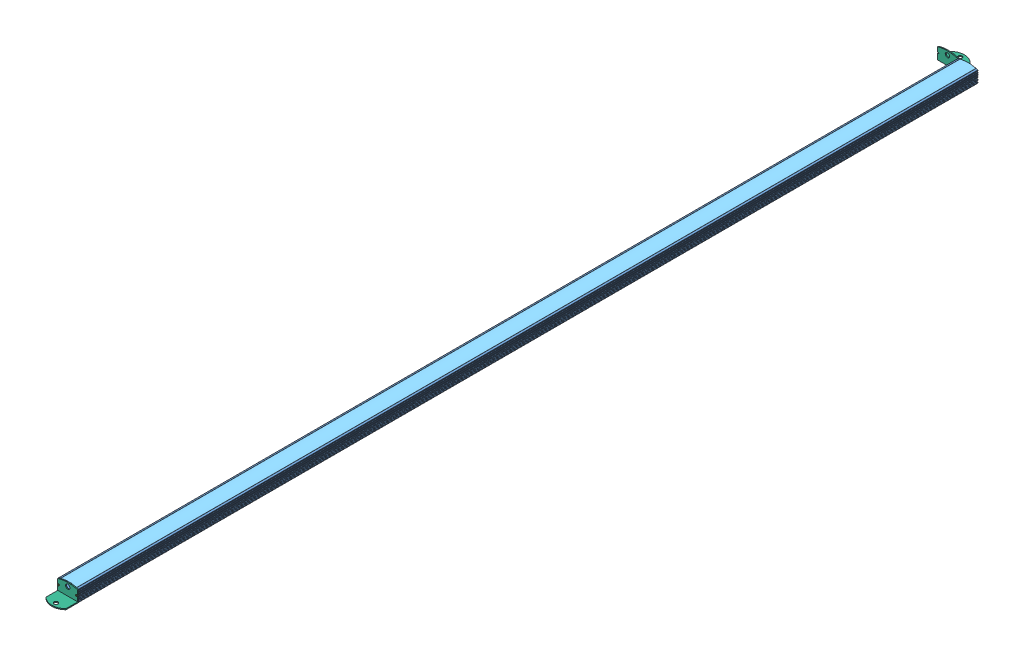
SolidWorks assembly lampara 54 leds, configuration Predeterminado. Lengths in mm.
Overall size (41.54 13.32 954.48).
132 component instances, 7 part files, 14 mates.
Components (placement in the parent):
- disipador-1: disipador [Predeterminado] at (27.3398 -156.7696 2146.1688) x (-1 0 0) z (0 -1 0) size (20.48 920 12.19)
- 5cmLedStrip-1: 5cmLedStrip [Default] at (81.127 -174.1929 2106.2883) x (0 0 1) z (-1 0 0) size (50.19 2.7 12.2)
  - stripPad-1: stripPad [Default] at (-20.1195 23.8233 53.0068) size (50.19 1.3 12.2)
  - led5050-1: led5050 [Default] at (-14.6195 25.2233 49.5068) size (5.4 1.5 5)
  - Resistor1206-1: Resistor1206 [Default] at (-2.8195 25.0233 48.6068) x (0 0 -1) z (1 0 0) size (3.2 0.7 1.6)
  - led5050-2: led5050 [Default] at (2.3805 25.2233 49.5068) size (5.4 1.5 5)
  - led5050-3: led5050 [Default] at (19.3805 25.2233 49.5068) size (5.4 1.5 5)
  - Resistor1206-2: Resistor1206 [Default] at (14.1805 25.0233 48.6068) x (0 0 -1) z (1 0 0) size (3.2 0.7 1.6)
- 5cmLedStrip-2: 5cmLedStrip [Default] at (81.127 -174.1929 2056.2883) x (0 0 1) z (-1 0 0) size (50.19 2.7 12.2)
  - stripPad-1: stripPad [Default] at (-20.1195 23.8233 53.0068) size (50.19 1.3 12.2)
  - led5050-1: led5050 [Default] at (-14.6195 25.2233 49.5068) size (5.4 1.5 5)
  - Resistor1206-1: Resistor1206 [Default] at (-2.8195 25.0233 48.6068) x (0 0 -1) z (1 0 0) size (3.2 0.7 1.6)
  - led5050-2: led5050 [Default] at (2.3805 25.2233 49.5068) size (5.4 1.5 5)
  - led5050-3: led5050 [Default] at (19.3805 25.2233 49.5068) size (5.4 1.5 5)
  - Resistor1206-2: Resistor1206 [Default] at (14.1805 25.0233 48.6068) x (0 0 -1) z (1 0 0) size (3.2 0.7 1.6)
- 5cmLedStrip-3: 5cmLedStrip [Default] at (81.127 -174.1929 2006.2883) x (0 0 1) z (-1 0 0) size (50.19 2.7 12.2)
  - stripPad-1: stripPad [Default] at (-20.1195 23.8233 53.0068) size (50.19 1.3 12.2)
  - led5050-1: led5050 [Default] at (-14.6195 25.2233 49.5068) size (5.4 1.5 5)
  - Resistor1206-1: Resistor1206 [Default] at (-2.8195 25.0233 48.6068) x (0 0 -1) z (1 0 0) size (3.2 0.7 1.6)
  - led5050-2: led5050 [Default] at (2.3805 25.2233 49.5068) size (5.4 1.5 5)
  - led5050-3: led5050 [Default] at (19.3805 25.2233 49.5068) size (5.4 1.5 5)
  - Resistor1206-2: Resistor1206 [Default] at (14.1805 25.0233 48.6068) x (0 0 -1) z (1 0 0) size (3.2 0.7 1.6)
- 5cmLedStrip-4: 5cmLedStrip [Default] at (81.127 -174.1929 1956.2883) x (0 0 1) z (-1 0 0) size (50.19 2.7 12.2)
  - stripPad-1: stripPad [Default] at (-20.1195 23.8233 53.0068) size (50.19 1.3 12.2)
  - led5050-1: led5050 [Default] at (-14.6195 25.2233 49.5068) size (5.4 1.5 5)
  - Resistor1206-1: Resistor1206 [Default] at (-2.8195 25.0233 48.6068) x (0 0 -1) z (1 0 0) size (3.2 0.7 1.6)
  - led5050-2: led5050 [Default] at (2.3805 25.2233 49.5068) size (5.4 1.5 5)
  - led5050-3: led5050 [Default] at (19.3805 25.2233 49.5068) size (5.4 1.5 5)
  - Resistor1206-2: Resistor1206 [Default] at (14.1805 25.0233 48.6068) x (0 0 -1) z (1 0 0) size (3.2 0.7 1.6)
- 5cmLedStrip-5: 5cmLedStrip [Default] at (81.127 -174.1929 1906.2883) x (0 0 1) z (-1 0 0) size (50.19 2.7 12.2)
  - stripPad-1: stripPad [Default] at (-20.1195 23.8233 53.0068) size (50.19 1.3 12.2)
  - led5050-1: led5050 [Default] at (-14.6195 25.2233 49.5068) size (5.4 1.5 5)
  - Resistor1206-1: Resistor1206 [Default] at (-2.8195 25.0233 48.6068) x (0 0 -1) z (1 0 0) size (3.2 0.7 1.6)
  - led5050-2: led5050 [Default] at (2.3805 25.2233 49.5068) size (5.4 1.5 5)
  - led5050-3: led5050 [Default] at (19.3805 25.2233 49.5068) size (5.4 1.5 5)
  - Resistor1206-2: Resistor1206 [Default] at (14.1805 25.0233 48.6068) x (0 0 -1) z (1 0 0) size (3.2 0.7 1.6)
- 5cmLedStrip-6: 5cmLedStrip [Default] at (81.127 -174.1929 1856.2883) x (0 0 1) z (-1 0 0) size (50.19 2.7 12.2)
  - stripPad-1: stripPad [Default] at (-20.1195 23.8233 53.0068) size (50.19 1.3 12.2)
  - led5050-1: led5050 [Default] at (-14.6195 25.2233 49.5068) size (5.4 1.5 5)
  - Resistor1206-1: Resistor1206 [Default] at (-2.8195 25.0233 48.6068) x (0 0 -1) z (1 0 0) size (3.2 0.7 1.6)
  - led5050-2: led5050 [Default] at (2.3805 25.2233 49.5068) size (5.4 1.5 5)
  - led5050-3: led5050 [Default] at (19.3805 25.2233 49.5068) size (5.4 1.5 5)
  - Resistor1206-2: Resistor1206 [Default] at (14.1805 25.0233 48.6068) x (0 0 -1) z (1 0 0) size (3.2 0.7 1.6)
- 5cmLedStrip-7: 5cmLedStrip [Default] at (81.127 -174.1929 1806.2883) x (0 0 1) z (-1 0 0) size (50.19 2.7 12.2)
  - stripPad-1: stripPad [Default] at (-20.1195 23.8233 53.0068) size (50.19 1.3 12.2)
  - led5050-1: led5050 [Default] at (-14.6195 25.2233 49.5068) size (5.4 1.5 5)
  - Resistor1206-1: Resistor1206 [Default] at (-2.8195 25.0233 48.6068) x (0 0 -1) z (1 0 0) size (3.2 0.7 1.6)
  - led5050-2: led5050 [Default] at (2.3805 25.2233 49.5068) size (5.4 1.5 5)
  - led5050-3: led5050 [Default] at (19.3805 25.2233 49.5068) size (5.4 1.5 5)
  - Resistor1206-2: Resistor1206 [Default] at (14.1805 25.0233 48.6068) x (0 0 -1) z (1 0 0) size (3.2 0.7 1.6)
- 5cmLedStrip-8: 5cmLedStrip [Default] at (81.127 -174.1929 1756.2883) x (0 0 1) z (-1 0 0) size (50.19 2.7 12.2)
  - stripPad-1: stripPad [Default] at (-20.1195 23.8233 53.0068) size (50.19 1.3 12.2)
  - led5050-1: led5050 [Default] at (-14.6195 25.2233 49.5068) size (5.4 1.5 5)
  - Resistor1206-1: Resistor1206 [Default] at (-2.8195 25.0233 48.6068) x (0 0 -1) z (1 0 0) size (3.2 0.7 1.6)
  - led5050-2: led5050 [Default] at (2.3805 25.2233 49.5068) size (5.4 1.5 5)
  - led5050-3: led5050 [Default] at (19.3805 25.2233 49.5068) size (5.4 1.5 5)
  - Resistor1206-2: Resistor1206 [Default] at (14.1805 25.0233 48.6068) x (0 0 -1) z (1 0 0) size (3.2 0.7 1.6)
- 5cmLedStrip-9: 5cmLedStrip [Default] at (81.127 -174.1929 1706.2883) x (0 0 1) z (-1 0 0) size (50.19 2.7 12.2)
  - stripPad-1: stripPad [Default] at (-20.1195 23.8233 53.0068) size (50.19 1.3 12.2)
  - led5050-1: led5050 [Default] at (-14.6195 25.2233 49.5068) size (5.4 1.5 5)
  - Resistor1206-1: Resistor1206 [Default] at (-2.8195 25.0233 48.6068) x (0 0 -1) z (1 0 0) size (3.2 0.7 1.6)
  - led5050-2: led5050 [Default] at (2.3805 25.2233 49.5068) size (5.4 1.5 5)
  - led5050-3: led5050 [Default] at (19.3805 25.2233 49.5068) size (5.4 1.5 5)
  - Resistor1206-2: Resistor1206 [Default] at (14.1805 25.0233 48.6068) x (0 0 -1) z (1 0 0) size (3.2 0.7 1.6)
- 5cmLedStrip-10: 5cmLedStrip [Default] at (81.127 -174.1929 1656.2883) x (0 0 1) z (-1 0 0) size (50.19 2.7 12.2)
  - stripPad-1: stripPad [Default] at (-20.1195 23.8233 53.0068) size (50.19 1.3 12.2)
  - led5050-1: led5050 [Default] at (-14.6195 25.2233 49.5068) size (5.4 1.5 5)
  - Resistor1206-1: Resistor1206 [Default] at (-2.8195 25.0233 48.6068) x (0 0 -1) z (1 0 0) size (3.2 0.7 1.6)
  - led5050-2: led5050 [Default] at (2.3805 25.2233 49.5068) size (5.4 1.5 5)
  - led5050-3: led5050 [Default] at (19.3805 25.2233 49.5068) size (5.4 1.5 5)
  - Resistor1206-2: Resistor1206 [Default] at (14.1805 25.0233 48.6068) x (0 0 -1) z (1 0 0) size (3.2 0.7 1.6)
- 5cmLedStrip-11: 5cmLedStrip [Default] at (81.127 -174.1929 1606.2883) x (0 0 1) z (-1 0 0) size (50.19 2.7 12.2)
  - stripPad-1: stripPad [Default] at (-20.1195 23.8233 53.0068) size (50.19 1.3 12.2)
  - led5050-1: led5050 [Default] at (-14.6195 25.2233 49.5068) size (5.4 1.5 5)
  - Resistor1206-1: Resistor1206 [Default] at (-2.8195 25.0233 48.6068) x (0 0 -1) z (1 0 0) size (3.2 0.7 1.6)
  - led5050-2: led5050 [Default] at (2.3805 25.2233 49.5068) size (5.4 1.5 5)
  - led5050-3: led5050 [Default] at (19.3805 25.2233 49.5068) size (5.4 1.5 5)
  - Resistor1206-2: Resistor1206 [Default] at (14.1805 25.0233 48.6068) x (0 0 -1) z (1 0 0) size (3.2 0.7 1.6)
- 5cmLedStrip-12: 5cmLedStrip [Default] at (81.127 -174.1929 1556.2883) x (0 0 1) z (-1 0 0) size (50.19 2.7 12.2)
  - stripPad-1: stripPad [Default] at (-20.1195 23.8233 53.0068) size (50.19 1.3 12.2)
  - led5050-1: led5050 [Default] at (-14.6195 25.2233 49.5068) size (5.4 1.5 5)
  - Resistor1206-1: Resistor1206 [Default] at (-2.8195 25.0233 48.6068) x (0 0 -1) z (1 0 0) size (3.2 0.7 1.6)
  - led5050-2: led5050 [Default] at (2.3805 25.2233 49.5068) size (5.4 1.5 5)
  - led5050-3: led5050 [Default] at (19.3805 25.2233 49.5068) size (5.4 1.5 5)
  - Resistor1206-2: Resistor1206 [Default] at (14.1805 25.0233 48.6068) x (0 0 -1) z (1 0 0) size (3.2 0.7 1.6)
- 5cmLedStrip-13: 5cmLedStrip [Default] at (81.127 -174.1929 1506.2883) x (0 0 1) z (-1 0 0) size (50.19 2.7 12.2)
  - stripPad-1: stripPad [Default] at (-20.1195 23.8233 53.0068) size (50.19 1.3 12.2)
  - led5050-1: led5050 [Default] at (-14.6195 25.2233 49.5068) size (5.4 1.5 5)
  - Resistor1206-1: Resistor1206 [Default] at (-2.8195 25.0233 48.6068) x (0 0 -1) z (1 0 0) size (3.2 0.7 1.6)
  - led5050-2: led5050 [Default] at (2.3805 25.2233 49.5068) size (5.4 1.5 5)
  - led5050-3: led5050 [Default] at (19.3805 25.2233 49.5068) size (5.4 1.5 5)
  - Resistor1206-2: Resistor1206 [Default] at (14.1805 25.0233 48.6068) x (0 0 -1) z (1 0 0) size (3.2 0.7 1.6)
- 5cmLedStrip-14: 5cmLedStrip [Default] at (81.127 -174.1929 1456.2883) x (0 0 1) z (-1 0 0) size (50.19 2.7 12.2)
  - stripPad-1: stripPad [Default] at (-20.1195 23.8233 53.0068) size (50.19 1.3 12.2)
  - led5050-1: led5050 [Default] at (-14.6195 25.2233 49.5068) size (5.4 1.5 5)
  - Resistor1206-1: Resistor1206 [Default] at (-2.8195 25.0233 48.6068) x (0 0 -1) z (1 0 0) size (3.2 0.7 1.6)
  - led5050-2: led5050 [Default] at (2.3805 25.2233 49.5068) size (5.4 1.5 5)
  - led5050-3: led5050 [Default] at (19.3805 25.2233 49.5068) size (5.4 1.5 5)
  - Resistor1206-2: Resistor1206 [Default] at (14.1805 25.0233 48.6068) x (0 0 -1) z (1 0 0) size (3.2 0.7 1.6)
- 5cmLedStrip-15: 5cmLedStrip [Default] at (81.127 -174.1929 1406.2883) x (0 0 1) z (-1 0 0) size (50.19 2.7 12.2)
  - stripPad-1: stripPad [Default] at (-20.1195 23.8233 53.0068) size (50.19 1.3 12.2)
  - led5050-1: led5050 [Default] at (-14.6195 25.2233 49.5068) size (5.4 1.5 5)
  - Resistor1206-1: Resistor1206 [Default] at (-2.8195 25.0233 48.6068) x (0 0 -1) z (1 0 0) size (3.2 0.7 1.6)
  - led5050-2: led5050 [Default] at (2.3805 25.2233 49.5068) size (5.4 1.5 5)
  - led5050-3: led5050 [Default] at (19.3805 25.2233 49.5068) size (5.4 1.5 5)
  - Resistor1206-2: Resistor1206 [Default] at (14.1805 25.0233 48.6068) x (0 0 -1) z (1 0 0) size (3.2 0.7 1.6)
- 5cmLedStrip-16: 5cmLedStrip [Default] at (81.127 -174.1929 1356.2883) x (0 0 1) z (-1 0 0) size (50.19 2.7 12.2)
  - stripPad-1: stripPad [Default] at (-20.1195 23.8233 53.0068) size (50.19 1.3 12.2)
  - led5050-1: led5050 [Default] at (-14.6195 25.2233 49.5068) size (5.4 1.5 5)
  - Resistor1206-1: Resistor1206 [Default] at (-2.8195 25.0233 48.6068) x (0 0 -1) z (1 0 0) size (3.2 0.7 1.6)
  - led5050-2: led5050 [Default] at (2.3805 25.2233 49.5068) size (5.4 1.5 5)
  - led5050-3: led5050 [Default] at (19.3805 25.2233 49.5068) size (5.4 1.5 5)
  - Resistor1206-2: Resistor1206 [Default] at (14.1805 25.0233 48.6068) x (0 0 -1) z (1 0 0) size (3.2 0.7 1.6)
- 5cmLedStrip-17: 5cmLedStrip [Default] at (81.127 -174.1929 1306.2883) x (0 0 1) z (-1 0 0) size (50.19 2.7 12.2)
  - stripPad-1: stripPad [Default] at (-20.1195 23.8233 53.0068) size (50.19 1.3 12.2)
  - led5050-1: led5050 [Default] at (-14.6195 25.2233 49.5068) size (5.4 1.5 5)
  - Resistor1206-1: Resistor1206 [Default] at (-2.8195 25.0233 48.6068) x (0 0 -1) z (1 0 0) size (3.2 0.7 1.6)
  - led5050-2: led5050 [Default] at (2.3805 25.2233 49.5068) size (5.4 1.5 5)
  - led5050-3: led5050 [Default] at (19.3805 25.2233 49.5068) size (5.4 1.5 5)
  - Resistor1206-2: Resistor1206 [Default] at (14.1805 25.0233 48.6068) x (0 0 -1) z (1 0 0) size (3.2 0.7 1.6)
- 5cmLedStrip-18: 5cmLedStrip [Default] at (81.127 -174.1929 1256.2883) x (0 0 1) z (-1 0 0) size (50.19 2.7 12.2)
  - stripPad-1: stripPad [Default] at (-20.1195 23.8233 53.0068) size (50.19 1.3 12.2)
  - led5050-1: led5050 [Default] at (-14.6195 25.2233 49.5068) size (5.4 1.5 5)
  - Resistor1206-1: Resistor1206 [Default] at (-2.8195 25.0233 48.6068) x (0 0 -1) z (1 0 0) size (3.2 0.7 1.6)
  - led5050-2: led5050 [Default] at (2.3805 25.2233 49.5068) size (5.4 1.5 5)
  - led5050-3: led5050 [Default] at (19.3805 25.2233 49.5068) size (5.4 1.5 5)
  - Resistor1206-2: Resistor1206 [Default] at (14.1805 25.0233 48.6068) x (0 0 -1) z (1 0 0) size (3.2 0.7 1.6)
- tapa-1: tapa [Predeterminado] at (53.6758 -145.894 1226.1688) x (1 0 0) z (0 -1 0) size (16.72 920 4.66)
- tapabase-1: tapabase [Predeterminado] at (85.5022 -150.6739 2146.1688) x (1 0 0) z (0 -1 0) size (20.48 17.24 13.09)
- tapabase-2: tapabase [Predeterminado] at (-38.2589 -150.6739 1226.1688) x (-1 0 0) z (0 -1 0) size (20.48 17.24 13.09)
- flat head miniature screw_ai-2: flat head miniature screw_ai [SL-FHM1-MINI 0.0394-102x0.16x0.16-N] at (43.4301 -150.2496 2147.841) x (0 0 -1) z (1 0 0) size (4.06 1.83 1.8)
- flat head miniature screw_ai-3: flat head miniature screw_ai [SL-FHM1-MINI 0.0394-102x0.16x0.16-N] at (24.8701 -150.2496 2147.5297) x (0 0 -1) z (1 0 0) size (4.06 1.83 1.8)
Mates (geometry in assembly coordinates):
- Coincidente1: coincident anti-aligned: plane of disipador-1 through (40.2777 -150.3696 1226.1688) normal (0 1 0); plane of 5cmLedStrip-1/stripPad-1 through (28.1201 -150.3696 2086.1688) normal (0 -1 0)
- Distancia1: distance = 10 mm aligned: plane of 5cmLedStrip-1/stripPad-1 through (28.1201 -149.2696 2136.1688) normal (0 0 1); plane of disipador-1 through (42.6101 -156.4696 2146.1688) normal (0 0 1)
- Distancia3: distance = 5.05 mm anti-aligned: plane of 5cmLedStrip-1/led5050-3 through (36.6201 -147.6696 2125.6688) normal (1 0 0); plane of disipador-1 through (41.6701 -145.7829 1226.1688) normal (-1 0 0)
- Concéntrica1: concentric aligned: circle of disipador-1; circle of tapa-1
- Coincidente5: coincident anti-aligned: circle of disipador-1; circle of tapa-1
- Coincidente6: coincident anti-aligned: plane of disipador-1 through (42.6101 -156.4696 2146.1688) normal (0 0 1); plane of tapabase-1 through (44.1901 -145.3363 2146.1688) normal (0 0 -1)
- Concéntrica2: concentric anti-aligned: circle of disipador-1; circle of tapabase-1
- Concéntrica3: concentric anti-aligned: cylinder of disipador-1 through (43.4301 -150.2496 1226.1688) axis (0 0 1) radius 0.6; cylinder of tapabase-1 through (43.4301 -150.2496 2147.1688) axis (0 0 -1) radius 0.6
- Coincidente8: coincident anti-aligned: plane of disipador-1 through (42.6101 -156.4696 1226.1688) normal (0 0 -1); plane of tapabase-2 through (3.0532 -145.3363 1226.1688) normal (0 0 1)
- Coincidente9: coincident aligned: plane of disipador-1 through (24.1646 -156.7696 1226.1688) normal (0 -1 0); plane of tapabase-2 through (23.0787 -156.7696 1225.1688) normal (0 -1 0)
- Concéntrica7: concentric aligned: cylinder of tapabase-1 through (43.4301 -150.2496 2147.1688) axis (0 0 -1) radius 0.6; cone of flat head miniature screw_ai-2 through (43.4301 -150.2496 2147.7057) axis (0 0 -1)
- Concéntrica8: concentric aligned: cylinder of tapabase-1 through (24.8701 -150.2496 2147.1688) axis (0 0 -1) radius 0.6; cone of flat head miniature screw_ai-3 through (24.8701 -150.2496 2147.3944) axis (0 0 -1)
- Coincidente11: coincident aligned: plane of tapabase-1 through (44.1901 -145.3363 2147.1688) normal (0 0 1); circle of flat head miniature screw_ai-3
- Coincidente12: coincident anti-aligned: plane of tapabase-1 through (44.1901 -145.3363 2147.1688) normal (0 0 1); circle of flat head miniature screw_ai-2
